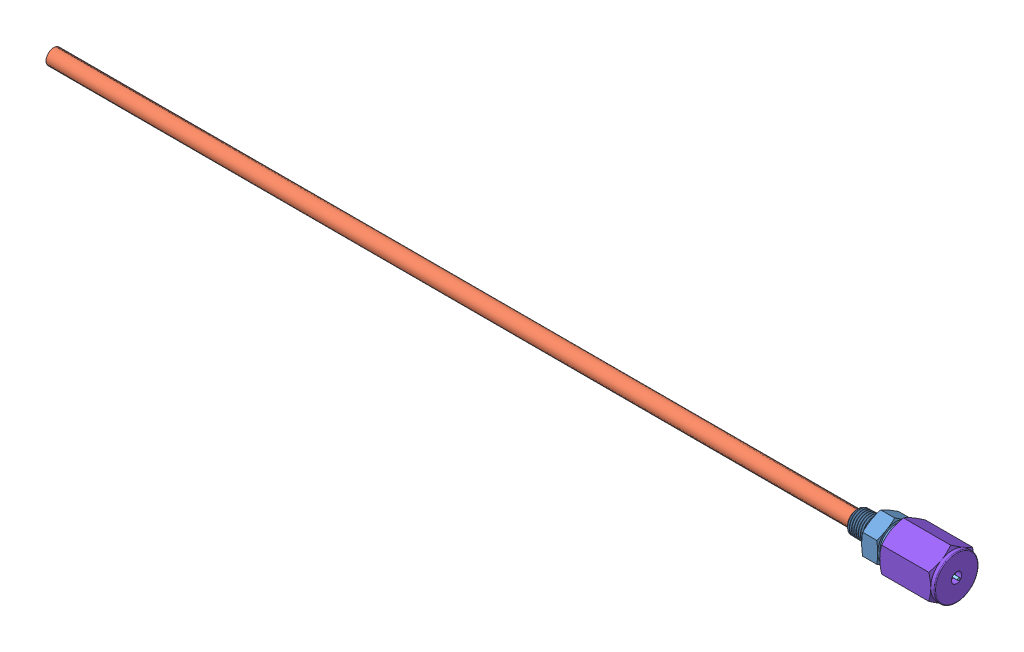
SolidWorks assembly LOX-level-sensor, configuration Default. Lengths in mm.
Overall size (559.37 31.16 26.99).
8 component instances, 8 part files, 7 mates.
Components (placement in the parent):
- custome npt mm reducer .25-.5 in-1: custome npt mm reducer .25-.5 in [48805K871] at (16.7362 23.7421 32.7818) size (43.79 25.66 23.34)
- 0.375 in diameter, 0.035in thick tube-1: 0.375 in diameter, 0.035in thick tube [Default] at (-1.0438 23.7421 32.7818) x (0 1 0) z (0 0 1) size (9.53 500 9.53)
- 0.1875 in rod-1: 0.1875 in rod [Default] at (20.1487 23.7421 32.7818) x (0 1 0) z (0 0 1) size (4.76 500 4.76)
- Copy of Part3-2: Copy of Part3 [Default] at (11.7362 23.7421 32.7818) size (41.59 12.7 12.7)
- Part4^LOX-level-sensor-2: Part4^LOX-level-sensor [Default] at (58.3237 23.7421 32.7818) size (39.76 4.76 4.76) (virtual)
- Part5-2: Part5 [Default] at (-492.5513 23.7421 32.7818) size (19.05 7.75 7.75)
- Part6-2: Part6 [Default] at (-223.4996 23.7421 32.7818) x (1 0 0) z (0 0.967077 0.254484) size (6.35 7.75 7.75)
- custome cap .5in-3: custome cap .5in [48805K26] at (39.9379 23.7421 32.7818) x (0 0 -1) z (1 0 0) size (26.99 31.16 34.12)
Mates (geometry in assembly coordinates):
- Coincident2: coincident anti-aligned: circle of custome npt mm reducer .25-.5 in-1; circle of Copy of Part3^LOX-level-sensor-2
- Coincident5: coincident aligned: circle of Copy of Part3^LOX-level-sensor-2; circle of Part4^LOX-level-sensor-2
- Coincident6: coincident aligned: circle of 0.1875 in rod-1; circle of Part4^LOX-level-sensor-2
- Coincident8: coincident aligned: circle of 0.1875 in rod-1; circle of Part5^LOX-level-sensor-2
- Concentric2: concentric anti-aligned: cylinder of 0.1875 in rod-1 through (18.5612 23.7421 32.7818) axis (1 0 0) radius 2.3813; cylinder of Part6^LOX-level-sensor-2 through (-223.4996 23.7421 32.7818) axis (-1 0 0) radius 2.3813
- Coincident9: coincident anti-aligned: circle of custome npt mm reducer .25-.5 in-1; circle of 0.375 in diameter, 0.035in thick tube-1
- Coincident10: coincident aligned: circle of Copy of Part3-2; circle of custome cap .5in-3
